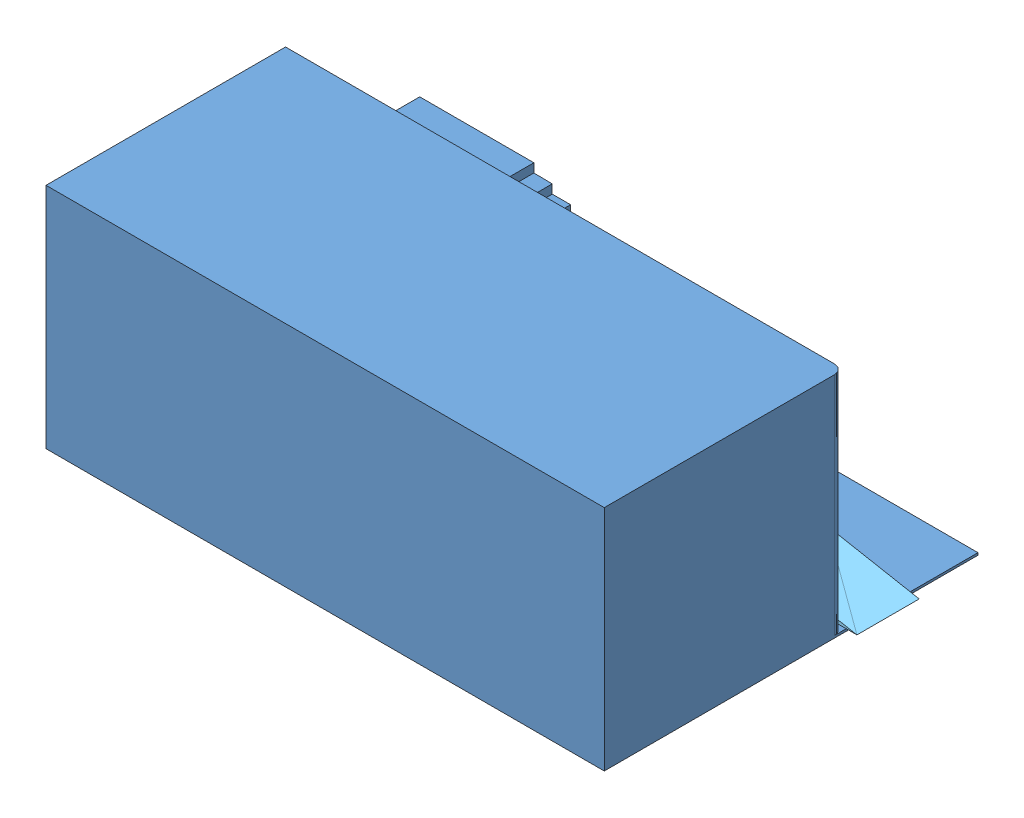
SolidWorks assembly Assembly-Scaled-Model, configuration Default. Lengths in mm.
Overall size (1193.2 751.74 780).
18 component instances, 5 part files, 12 mates.
Components (placement in the parent):
- Staircase-Scaled-Model-2: Staircase-Scaled-Model [Default] at (13.5647 114.8686 266.6765) x (0 0 1) z (-1 0 0) size (780 476.14 1165.21)
- 28BYJ48-1: 28BYJ48 [Default] at (459.6535 -36.0803 60.2925) x (1 -0.000001 0) z (0 0 -1) size (42.95 31.65 30.77)
- Assembly-Scaled-Conveyor-1: Assembly-Scaled-Conveyor [Default] at (230.4199 101.6486 265.1403) x (0 0 -1) z (0.914537 -0.404503 0) size (140 339.39 853.06)
  - Housing-Brace-1: Housing-Brace [Default] at (138.4638 -8.0875 9.7021) size (135 339.39 853.06)
  - Roller-1: Roller [Default] at (8.4638 -8.0875 156.4026) x (0 0 -1) z (-1 0 0) size (25 25 140)
  - Roller-3: Roller [Default] at (8.4638 -8.0875 -98.8974) x (0 0 -1) z (-1 0 0) size (25 25 140)
  - Roller-4: Roller [Default] at (8.4638 -8.0875 -13.7974) x (0 -0.056104 -0.998425) z (-1 0 0) size (25 25 140)
  - Roller-5: Roller [Default] at (8.4638 -8.0875 71.3026) x (0 0 -1) z (-1 0 0) size (25 25 140)
  - Roller-6: Roller [Default] at (8.4638 -8.0875 -183.9974) x (0 0 -1) z (-1 0 0) size (25 25 140)
  - Roller-7: Roller [Default] at (8.4638 -8.0875 -269.0974) x (0 0 -1) z (-1 0 0) size (25 25 140)
  - Roller-8: Roller [Default] at (8.4638 -8.0875 241.5026) x (0 0.199031 -0.979993) z (-1 0 0) size (25 25 140)
  - Roller-11: Roller [Default] at (8.4638 -18.3722 -315.5954) x (0 0.044275 -0.999019) z (-1 0 0) size (25 25 140)
  - Roller-18: Roller [Default] at (8.4638 0.865 331.1112) x (0 0.044275 -0.999019) z (-1 0 0) size (25 25 140)
  - Roller-19: Roller [Default] at (8.4638 -8.0875 299.6516) x (0 0.044275 -0.999019) z (-1 0 0) size (25 25 140)
  - Roller-20: Roller [Default] at (8.4638 23.5172 382.3253) x (0 0.044275 -0.999019) z (-1 0 0) size (25 25 140)
  - Roller-21: Roller [Default] at (8.4638 46.1694 433.5393) x (0 0.044275 -0.999019) z (-1 0 0) size (25 25 140)
- Ramp-1: Ramp [Default] at (711.3331 -52.7371 261.6765) x (0 0 -1) z (1 0 0) size (130 35.9 191.47)
- Ramp-3: Ramp [Default] at (-98.9353 188.5817 131.6765) x (0 0 1) z (-1 0 0) size (130 35.9 191.47)
Mates (geometry in assembly coordinates):
- Coincident10: coincident: plane of Staircase-Scaled-Model-2 through (-46.4353 188.5817 -13.3235) normal (1 0 0); line of Assembly-Scaled-Conveyor-1/Housing-Brace-1 through (-46.4353 188.3059 261.6765) axis (0 0 -1)
- Coincident12: coincident anti-aligned: plane of Staircase-Scaled-Model-2 through (880.4709 -52.7371 266.6765) normal (0 1 0); plane of Assembly-Scaled-Conveyor-1/Housing-Brace-1 through (498.5362 -52.7371 28.5941) normal (0 -1 0)
- Coincident13: coincident anti-aligned: plane of Staircase-Scaled-Model-2 through (880.4709 -52.7371 266.6765) normal (0 1 0); plane of 28BYJ48-1 through (459.6535 -52.7371 60.6698) normal (0 -1 0)
- Coincident14: coincident anti-aligned: plane of Staircase-Scaled-Model-2 through (880.4709 -52.7371 266.6765) normal (0 1 0); plane of Ramp-1 through (711.3331 -52.7371 261.6765) normal (0 -1 0)
- Coincident15: coincident anti-aligned: plane of Assembly-Scaled-Conveyor-1/Housing-Brace-1 through (711.3331 -52.7371 28.5941) normal (1 0 0); plane of Ramp-1 through (711.3331 -52.7371 261.6765) normal (-1 0 0)
- Coincident16: coincident aligned: plane of Assembly-Scaled-Conveyor-1/Housing-Brace-1 through (312.1815 -474.0641 131.6765) normal (0 0 -1); plane of Ramp-1 through (711.3331 -52.7371 131.6765) normal (0 0 -1)
- Coincident17: coincident anti-aligned: plane of Assembly-Scaled-Conveyor-1/Housing-Brace-1 through (-98.9353 224.2472 169.6286) normal (-1 0 0); plane of RAMP TOP-1 through (-98.9353 188.5817 131.6765) normal (1 0 0)
- Coincident18: coincident anti-aligned: plane of Staircase-Scaled-Model-2 through (-84.7353 188.5817 -13.3235) normal (0 1 0); plane of RAMP TOP-1 through (-98.9353 188.5817 131.6765) normal (0 -1 0)
- Coincident19: coincident aligned: plane of Assembly-Scaled-Conveyor-1/Housing-Brace-1 through (312.1815 -474.0641 131.6765) normal (0 0 -1); plane of RAMP TOP-1 through (-98.9353 188.5817 131.6765) normal (0 0 -1)
- Coincident20: coincident anti-aligned: plane of Assembly-Scaled-Conveyor-1/Housing-Brace-1 through (-98.9353 224.2472 169.6286) normal (-1 0 0); plane of Ramp-3 through (-98.9353 188.5817 131.6765) normal (1 0 0)
- Coincident22: coincident aligned: plane of Assembly-Scaled-Conveyor-1/Housing-Brace-1 through (312.1815 -474.0641 131.6765) normal (0 0 -1); plane of Ramp-3 through (-98.9353 188.5817 131.6765) normal (0 0 -1)
- Coincident23: coincident anti-aligned: plane of Staircase-Scaled-Model-2 through (-84.7353 188.5817 -13.3235) normal (0 1 0); plane of Ramp-3 through (-98.9353 188.5817 131.6765) normal (0 -1 0)
